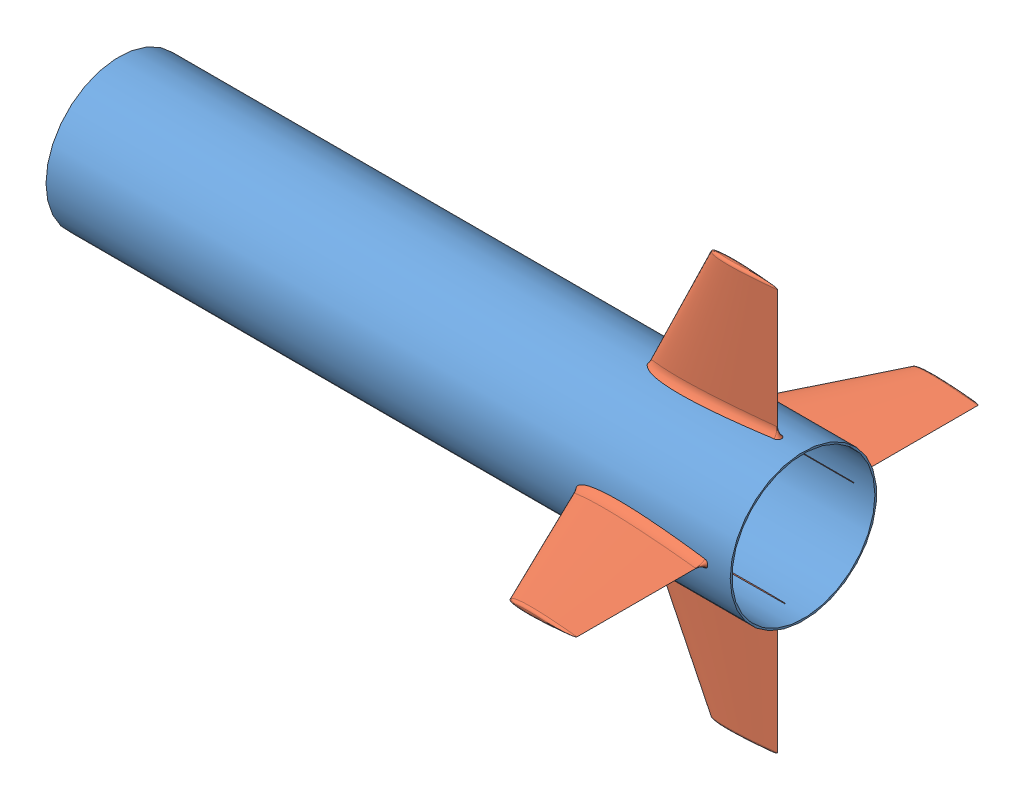
SolidWorks assembly Tube_Fin Assem V2, configuration Default. Lengths in mm.
Overall size (790 472.21 472.21).
5 component instances, 2 part files, 3 mates.
Components (placement in the parent):
- Lower body tube-1: Lower body tube [Default] at (-419.5819 4.5927 9.8514) size (790 169.1 169.1)
- Fin 150_75_150 curved-1: Fin 150_75_150 curved [Default] at (190.2852 4.5927 -69.6486) x (1 0 0) z (0 0 -1) size (164.95 35.88 158.03)
- Fin 150_75_150 curved-2: Fin 150_75_150 curved [Default] at (190.2852 84.0927 9.8514) x (1 0 0) z (0 1 0) size (164.95 35.88 158.03)
- Fin 150_75_150 curved-3: Fin 150_75_150 curved [Default] at (190.2852 4.5927 89.3514) size (164.95 35.88 158.03)
- Fin 150_75_150 curved-4: Fin 150_75_150 curved [Default] at (190.2852 -74.9073 9.8514) x (1 0 0) z (0 -1 0) size (164.95 35.88 158.03)
Mates (geometry in assembly coordinates):
- Concentric1: concentric aligned: cylinder of Lower body tube-1 through (370.4181 4.5927 9.8514) axis (-1 0 0) radius 84.55; cylinder of Fin 150_75_150 curved-1 through (381.13 4.5927 9.8514) axis (-1 0 0) radius 82.5084
- Parallel1: parallel anti-aligned: plane of Fin 150_75_150 curved-1 through (286.121 4.5927 -224.6486) normal (0 0 -1); plane of assembly through (0 0 0) normal (0 0 1)
- Distance1: distance = 30 mm: plane of assembly; moEndPointRef_w of Fin 150_75_150 curved-1
